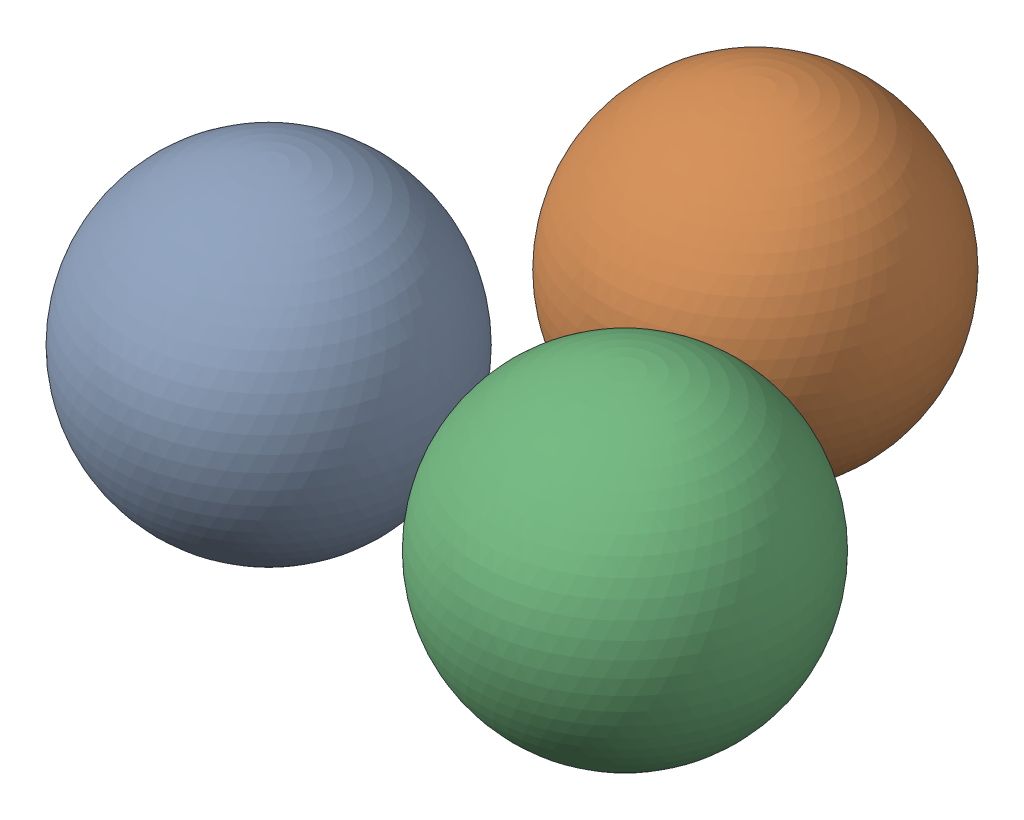
SolidWorks assembly 3-packing, configuration Default. Lengths in mm.
Overall size (90.96 42.67 84.49).
3 component instances, 1 part files, 3 mates.
Components (placement in the parent):
- golf ball-1: golf ball [Default] at (-24.1418 0 13.9383) size (42.67 42.67 42.67)
- golf ball-2: golf ball [Default] at (0 0 -27.8765) size (42.67 42.67 42.67)
- golf ball-3: golf ball [Default] at (24.1418 0 13.9383) size (42.67 42.67 42.67)
Mates (geometry in assembly coordinates):
- Coincident1: coincident: point of golf ball-1
- Coincident2: coincident: unknown of golf ball-2
- Coincident3: coincident: unknown of golf ball-3
